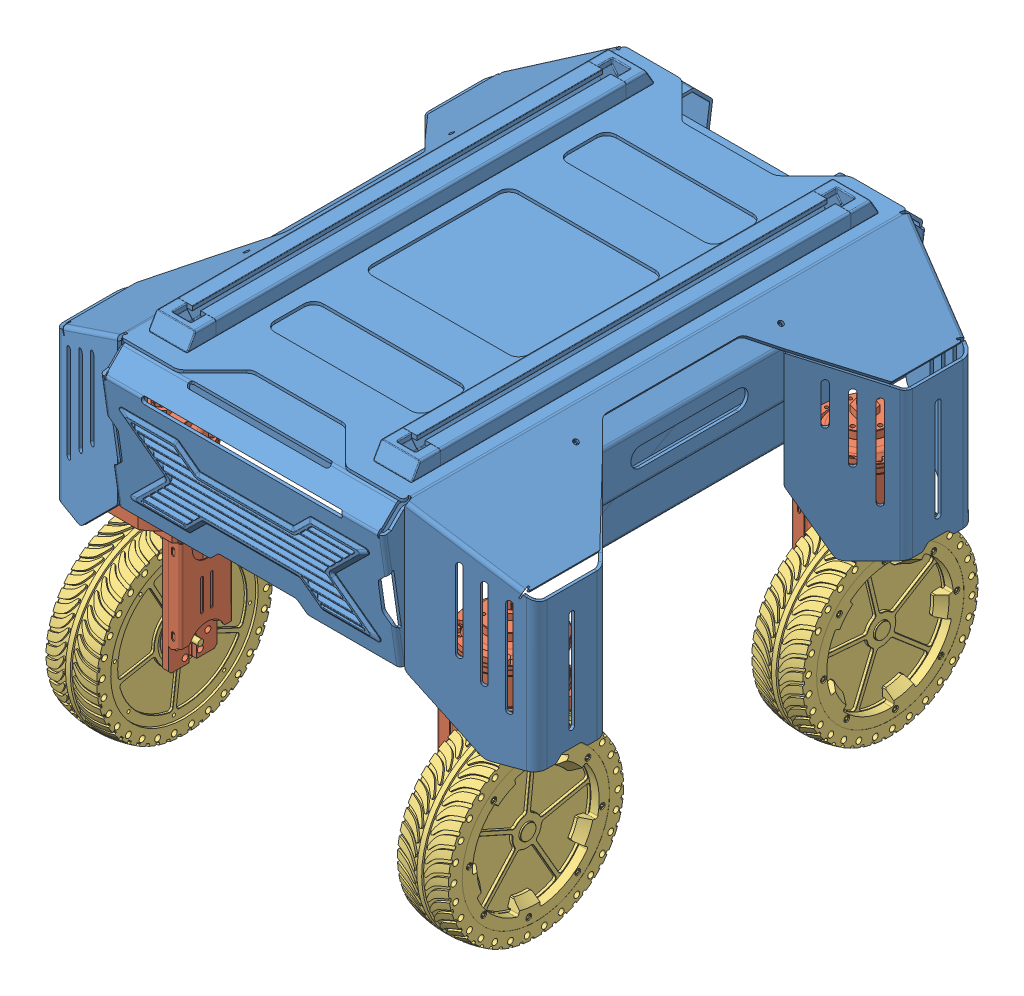
SolidWorks assembly ranger_mini, configuration Default. Lengths in mm.
Overall size (494 456.89 595.77).
9 component instances, 3 part files, 20 mates.
Components (placement in the parent):
- Ranger_mini_base-1: Ranger_mini_base [默认] at (-302.7246 192.8169 -87.9877) x (1 0 0) z (0 -1 0) size (494 557.51 226.67)
- Ranger mini axis-1: Ranger mini axis [默认] at (-303.5246 194.1169 -91.1835) x (1 0 0) z (0 -1 0) size (93.01 89.01 224.23)
- Ranger mini wheel-1: Ranger mini wheel [默认] at (42.1532 337.8416 294.6107) x (-1 0 0) z (0 -0.756253 0.654279) size (70.06 187 187)
- Ranger mini axis-3: Ranger mini axis [默认] at (-306.5246 194.1169 268.8165) x (1 0 0) z (0 -1 0) size (93.01 89.01 224.23)
- Ranger mini wheel-3: Ranger mini wheel [默认] at (39.1532 -223.8208 736.3506) x (-1 0 0) z (0 -0.111672 -0.993745) size (70.06 187 187)
- Ranger mini axis-5: Ranger mini axis [默认] at (39.1532 194.1169 826.3474) x (-1 0 0) z (0 -1 0) size (93.01 89.01 224.23)
- Ranger mini wheel-5: Ranger mini wheel [默认] at (-306.5246 331.0384 672.1725) x (1 0 0) z (0 -0.118126 -0.992999) size (70.06 187 187)
- Ranger mini axis-6: Ranger mini axis [默认] at (39.1532 194.1169 466.3474) x (-1 0 0) z (0 -1 0) size (93.01 89.01 224.23)
- Ranger mini wheel-6: Ranger mini wheel [默认] at (-306.5246 202.1201 -86.4747) x (1 0 0) z (0 -0.999581 -0.028948) size (70.06 187 187)
Mates (geometry in assembly coordinates):
- Coincident1: coincident anti-aligned: plane of Ranger mini axis-1 through (23.8143 35.4864 187.5819) normal (1 0 0); plane of Ranger mini wheel-1 through (23.8143 43.4641 180.7551) normal (-1 0 0)
- Concentric3: concentric aligned: cylinder of Ranger mini axis-1 through (79.8143 35.4864 187.5819) axis (-1 0 0) radius 4; cylinder of Ranger mini wheel-1 through (48.8143 35.4864 187.5819) axis (-1 0 0) radius 3
- Concentric5: concentric aligned: cylinder of Ranger mini wheel-3 through (45.8143 35.4864 547.5819) axis (-1 0 0) radius 3; cylinder of Ranger mini axis-3 through (76.8143 35.4864 547.5819) axis (-1 0 0) radius 4
- Coincident3: coincident anti-aligned: plane of Ranger mini wheel-3 through (20.8143 36.6023 558.0224) normal (-1 0 0); plane of Ranger mini axis-3 through (20.8143 35.4864 547.5819) normal (1 0 0)
- Concentric7: concentric aligned: cylinder of Ranger mini wheel-5 through (-313.1857 35.4864 547.5819) axis (1 0 0) radius 3; cylinder of Ranger mini axis-5 through (-344.1857 35.4864 547.5819) axis (1 0 0) radius 4
- Coincident5: coincident anti-aligned: plane of Ranger mini wheel-5 through (-288.1857 36.7832 558.0015) normal (1 0 0); plane of Ranger mini axis-5 through (-288.1857 35.4864 547.5819) normal (-1 0 0)
- Coincident6: coincident anti-aligned: plane of Ranger mini axis-6 through (-288.1857 35.4864 187.5819) normal (-1 0 0); plane of Ranger mini wheel-6 through (-288.1857 45.9834 187.829) normal (1 0 0)
- Concentric8: concentric aligned: cylinder of Ranger mini axis-6 through (-344.1857 35.4864 187.5819) axis (1 0 0) radius 4; cylinder of Ranger mini wheel-6 through (-313.1857 35.4864 187.5819) axis (1 0 0) radius 3
- Distance1: distance = 37.3 mm anti-aligned: plane of Ranger mini axis-3 through (76.8143 146.4864 522.5819) normal (1 0 0); plane of Ranger_mini_base-1 through (114.1143 134.4864 588.2421) normal (-1 0 0)
- Coincident9: coincident aligned: plane of Ranger_mini_base-1 through (114.1143 140.4864 588.2421) normal (0 -1 0); plane of Ranger mini axis-3 through (20.8143 140.4864 547.5819) normal (0 -1 0)
- Distance3: distance = 37.3 mm aligned: plane of Ranger_mini_base-1 through (-376.8857 134.4864 588.2421) normal (-1 0 0); plane of Ranger mini wheel-5 through (-339.5857 -39.4356 556.9066) normal (-1 0 0)
- Coincident12: coincident aligned: plane of Ranger_mini_base-1 through (-373.8857 140.4864 588.2421) normal (0 -1 0); plane of Ranger mini axis-5 through (-288.1857 140.4864 547.5819) normal (0 -1 0)
- Distance4: distance = 37.3 mm aligned: plane of Ranger mini axis-1 through (79.8143 146.4864 162.5819) normal (1 0 0); plane of Ranger_mini_base-1 through (117.1143 134.4864 147.9135) normal (1 0 0)
- Coincident14: coincident aligned: plane of Ranger_mini_base-1 through (114.1143 140.4864 147.9135) normal (0 -1 0); plane of Ranger mini axis-1 through (23.8143 140.4864 187.5819) normal (0 -1 0)
- Distance7: distance = 37.3 mm aligned: plane of Ranger mini wheel-6 through (-339.5857 33.7099 263.061) normal (-1 0 0); plane of Ranger_mini_base-1 through (-376.8857 134.4864 147.9135) normal (-1 0 0)
- Coincident18: coincident aligned: plane of Ranger_mini_base-1 through (-373.8857 140.4864 147.9135) normal (0 -1 0); plane of Ranger mini axis-6 through (-288.1857 140.4864 187.5819) normal (0 -1 0)
- Distance9: distance = 5 mm aligned: plane of Ranger_mini_base-1 through (-129.8857 308.4864 138.0778) normal (0 0 -1); plane of Ranger mini axis-6 through (-290.8957 148.4864 143.0778) normal (0 0 -1)
- Distance10: distance = 5 mm aligned: plane of Ranger_mini_base-1 through (-129.8857 308.4864 138.0778) normal (0 0 -1); plane of Ranger mini axis-1 through (26.5243 148.4864 143.0778) normal (0 0 -1)
- Distance12: distance = 307 mm anti-aligned: plane of Ranger mini axis-1 through (1.811 37.9877 214.5819) normal (0 0 1); plane of Ranger mini axis-3 through (10.811 37.9854 521.5819) normal (0 0 -1)
- Distance13: distance = 307 mm anti-aligned: plane of Ranger mini axis-6 through (-278.1823 37.9854 213.5819) normal (0 0 1); plane of Ranger mini axis-5 through (-266.1823 37.9877 520.5819) normal (0 0 -1)
